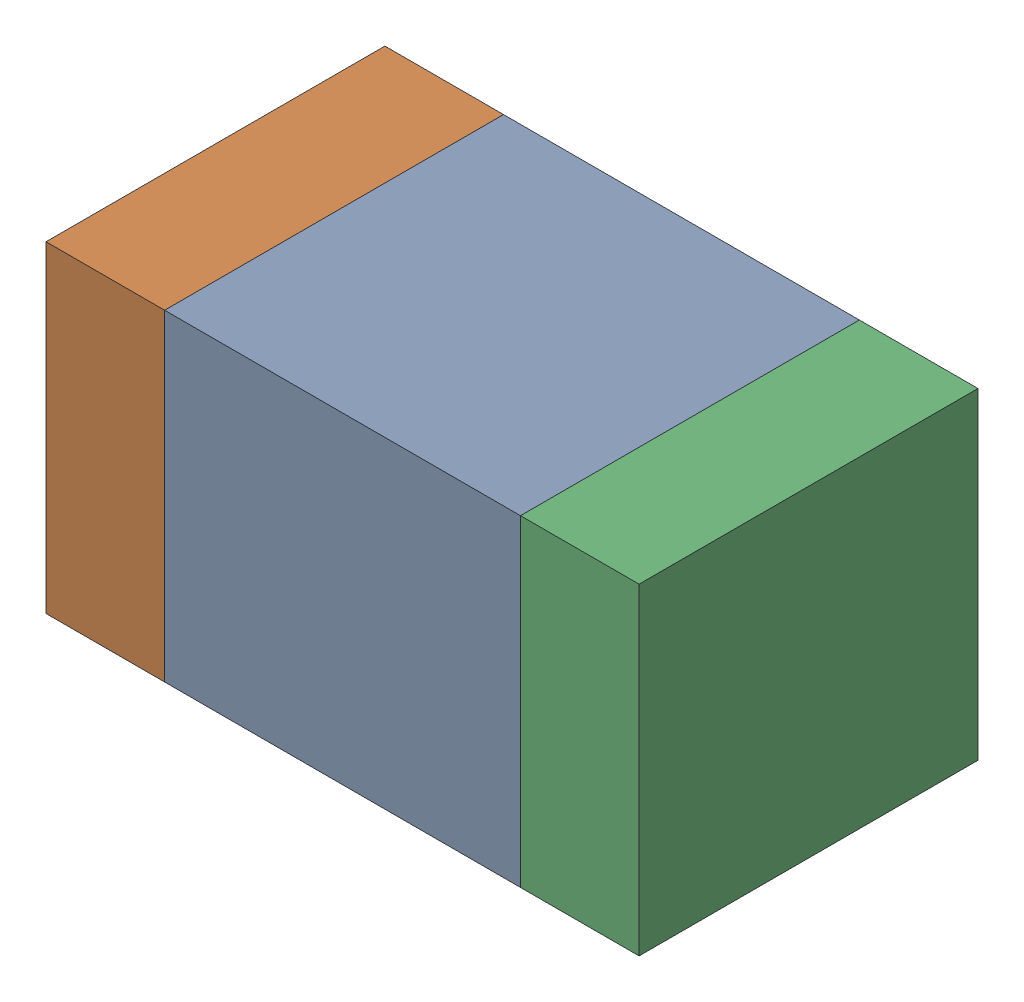
SolidWorks assembly C433PCB, configuration Default. Lengths in mm.
Overall size (1.75 0.95 1).
6 component instances, 2 part files, 0 mates.
Components (placement in the parent):
- 761616112-1: 761616112 [Default] at (120.7 105.8 -2.6638) size (1.05 0.95 1)
  - Extruded_14-1: Extruded_14 [Default] at origin size (1.05 0.95 1)
- 761616248-1: 761616248 [Default] at (120 105.8 -2.6638) size (0.35 0.95 1)
  - Extruded_15-1: Extruded_15 [Default] at origin size (0.35 0.95 1)
- 761616248-2: 761616248 [Default] at (121.4 105.8 -2.6638) size (0.35 0.95 1)
  - Extruded_15-1: Extruded_15 [Default] at origin size (0.35 0.95 1)
